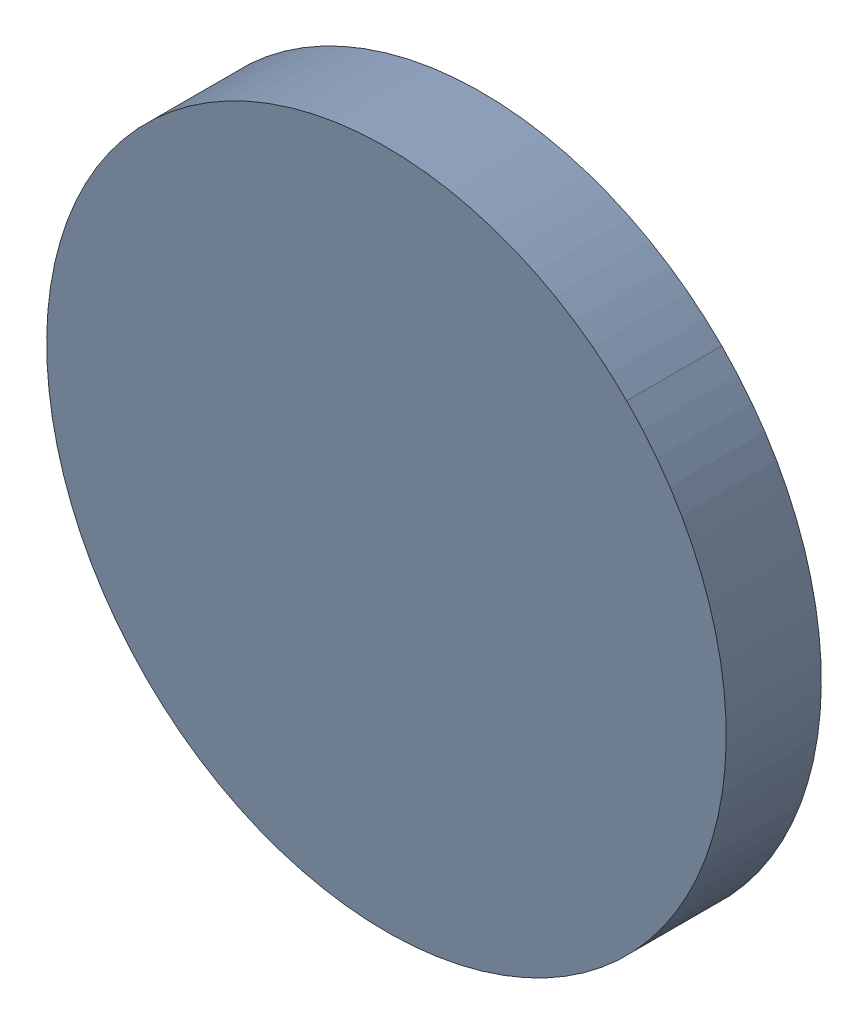
SolidWorks assembly Track (25.1mm,48.5mm)(25.1mm,48.5mm) on Top Layer, configuration Predeterminado. Lengths in mm.
Overall size (0.25 0.25 0.04).
2 component instances, 1 part files, 0 mates.
Components (placement in the parent):
- Track (25.1mm,48.5mm)(25.1mm,48.5mm) on Top Layer-1-1: Track (25.1mm,48.5mm)(25.1mm,48.5mm) on Top Layer-1 [Predeterminado] at (-68.317 -44.187 -0.0457) size (0.25 0.25 0.04)
  - Track (25.1mm,48.5mm)(25.1mm,48.5mm) on Top Layer-Part-1-1: Track (25.1mm,48.5mm)(25.1mm,48.5mm) on Top Layer-Part-1 [Predeterminado] at origin size (0.25 0.25 0.04)
